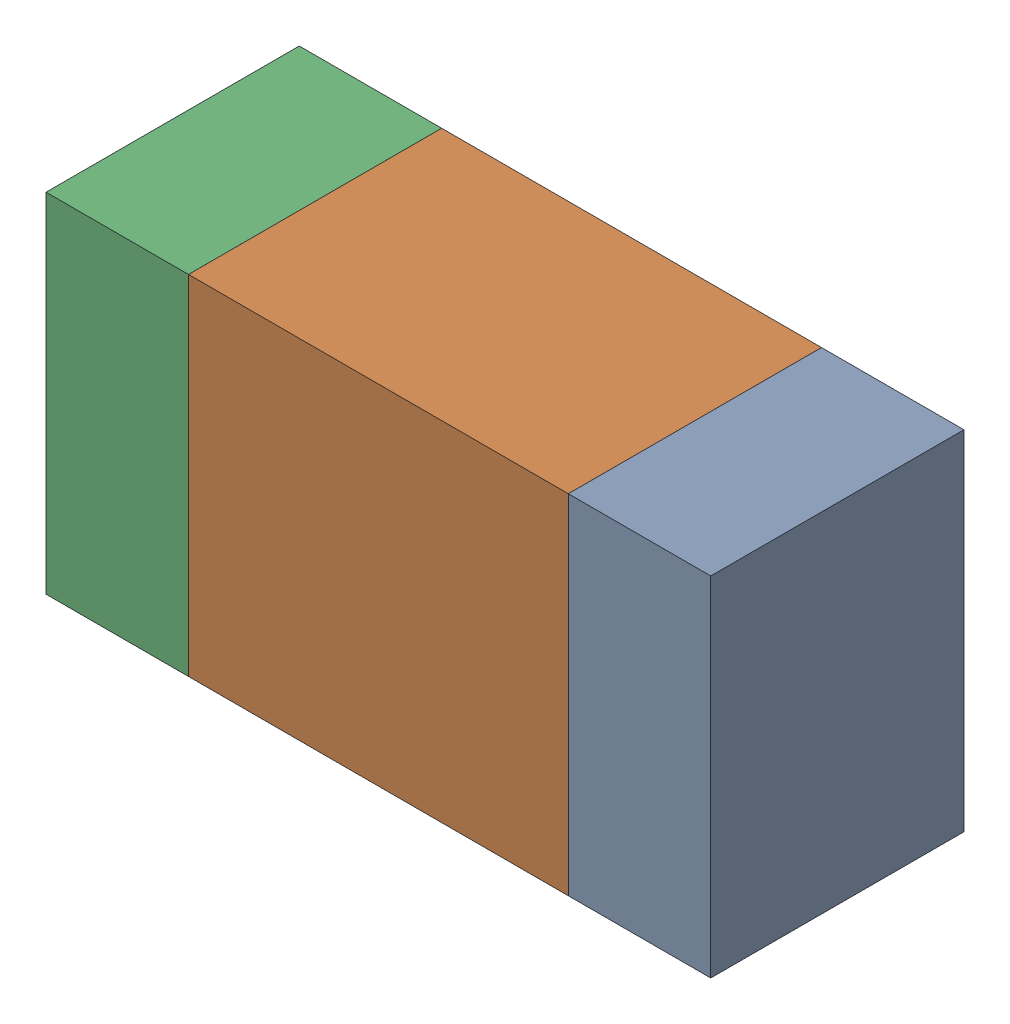
SolidWorks assembly R409PCB, configuration Default. Lengths in mm.
Overall size (1.05 0.55 0.4).
6 component instances, 2 part files, 0 mates.
Components (placement in the parent):
- 854785432-1: 854785432 [Default] at (121.1124 100.9999 0) size (0.22 0.55 0.4)
  - Extruded-1: Extruded [Default] at origin size (0.22 0.55 0.4)
- 854785568-1: 854785568 [Default] at (120.6999 100.9999 0) size (0.6 0.55 0.4)
  - Extruded_2-1: Extruded_2 [Default] at origin size (0.6 0.55 0.4)
- 854785432-2: 854785432 [Default] at (120.2874 100.9999 0) size (0.22 0.55 0.4)
  - Extruded-1: Extruded [Default] at origin size (0.22 0.55 0.4)
